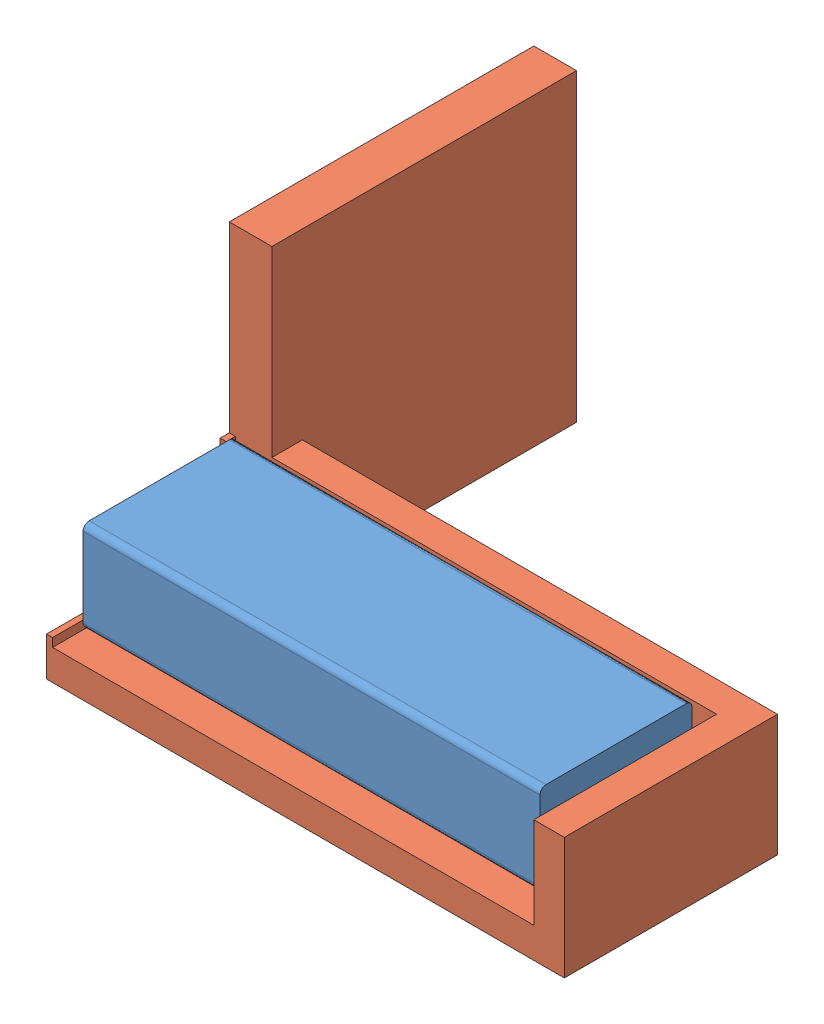
SolidWorks assembly apriltag_attachment_example, configuration Standard. Lengths in mm.
Overall size (85 50 80).
3 component instances, 3 part files, 6 mates.
Components (placement in the parent):
- block-1: block [Standard] at origin size (75 15 25)
- kalibriervorrichtung-1: kalibriervorrichtung [Standard] at (-24.9286 -5 12.9464) x (0 0 1) z (-1 0 0) size (80 50 85)
- schildchen-1: schildchen [Standard] at (-23.9286 13.4 -15.5536) x (0 0 -1) z (0 1 0) size (22 1 12)
Mates (geometry in assembly coordinates):
- Coincident2: coincident anti-aligned: plane of block-1 through (-23.9286 15 -17.0536) normal (0 0 -1); plane of kalibriervorrichtung-1 through (-24.9286 15 -17.0536) normal (0 0 1)
- Coincident3: coincident anti-aligned: plane of block-1 through (0 0 0) normal (0 -1 0); plane of kalibriervorrichtung-1 through (-24.9286 0 12.9464) normal (0 1 0)
- Coincident4: coincident anti-aligned: plane of block-1 through (-23.9286 15 -17.0536) normal (-1 0 0); plane of kalibriervorrichtung-1 through (-23.9286 1.4 12.9464) normal (1 0 0)
- Coincident5: coincident anti-aligned: plane of block-1 through (-23.9286 15 -17.0536) normal (-1 0 0); plane of schildchen-1 through (-23.9286 13.4 -15.5536) normal (1 0 0)
- Coincident6: coincident anti-aligned: plane of kalibriervorrichtung-1 through (-24.9286 1.4 12.9464) normal (0 1 0); plane of schildchen-1 through (-24.9286 1.4 6.4464) normal (0 -1 0)
- Coincident7: coincident anti-aligned: plane of kalibriervorrichtung-1 through (-24.9286 15 -15.5536) normal (0 0 1); plane of schildchen-1 through (-24.9286 1.4 -15.5536) normal (0 0 -1)
